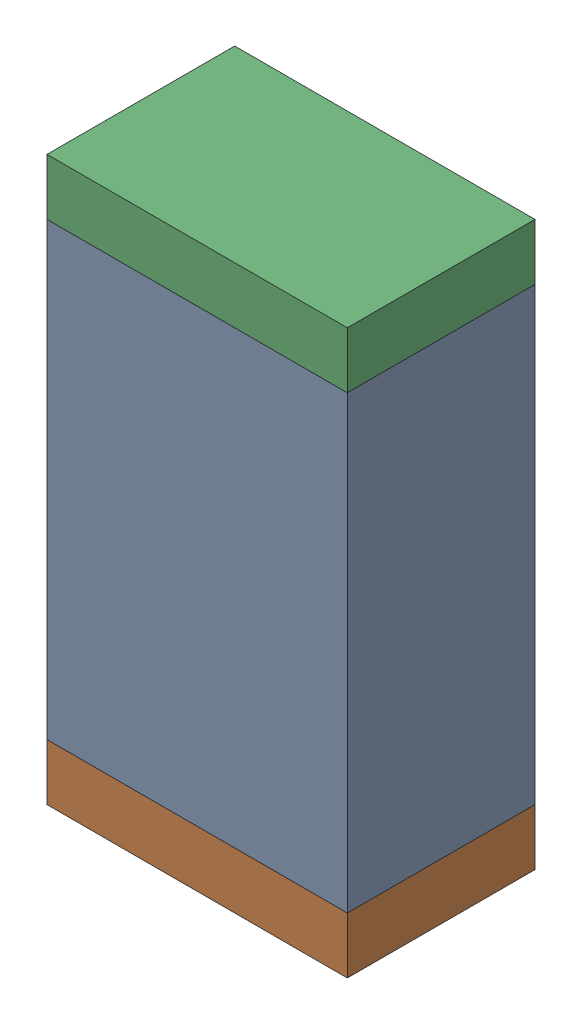
SolidWorks assembly R25, configuration Default. Lengths in mm.
Overall size (0.8 1.5 0.5).
6 component instances, 2 part files, 0 mates.
Components (placement in the parent):
- 810156976-1: 810156976 [Default] at (116.45 45.6 0) size (0.8 1.2 0.5)
  - Extruded_6-1: Extruded_6 [Default] at origin size (0.8 1.2 0.5)
- 810156592-1: 810156592 [Default] at (116.45 44.925 0) size (0.8 0.15 0.5)
  - Extruded_7-1: Extruded_7 [Default] at origin size (0.8 0.15 0.5)
- 810156592-2: 810156592 [Default] at (116.45 46.275 0) size (0.8 0.15 0.5)
  - Extruded_7-1: Extruded_7 [Default] at origin size (0.8 0.15 0.5)
